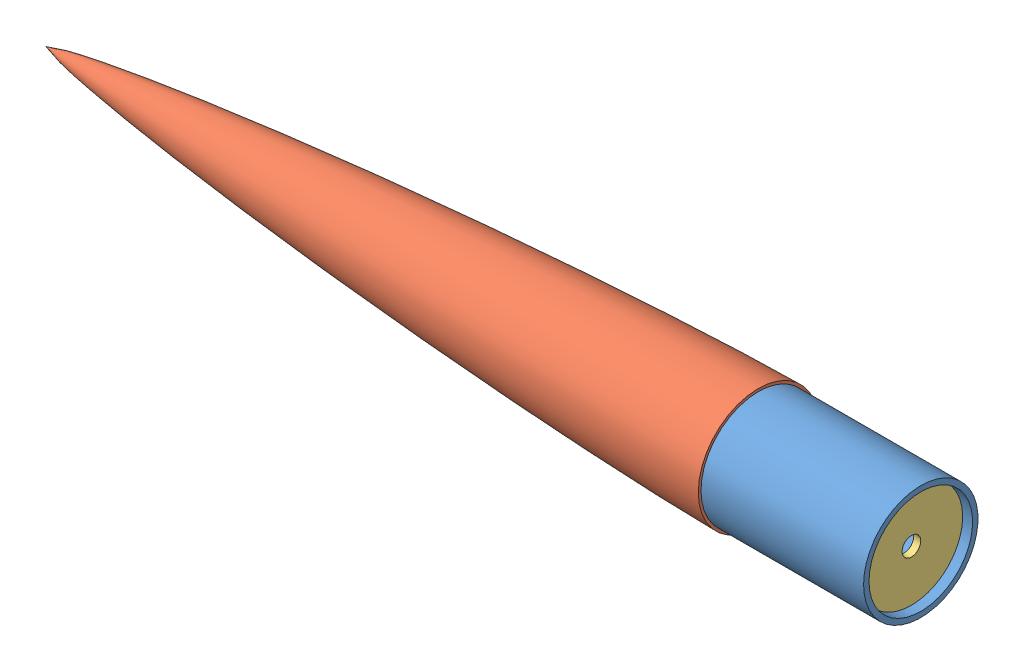
SolidWorks assembly Assem3, configuration Default. Lengths in mm.
Overall size (296.37 40.64 40.64).
3 component instances, 3 part files, 4 mates.
Components (placement in the parent):
- 3inFiberglassCoupler-1: 3inFiberglassCoupler [Default] at (-12.4673 3.7311 -16.4496) size (77.67 38.76 38.76)
- VonKarmanNoseCone-1: VonKarmanNoseCone [Default] at (-231.1613 3.7311 -16.4496) size (241.3 40.64 40.64)
- NoseConeBulkhead-1: NoseConeBulkhead [Default] at (59.6179 3.7311 -16.4496) size (2.41 34.67 34.67)
Mates (geometry in assembly coordinates):
- Concentric1: concentric aligned: cylinder of 3inFiberglassCoupler-1 through (65.2059 3.7311 -16.4496) axis (-1 0 0) radius 17.5514; circle of VonKarmanNoseCone-1
- Distance2: distance = 55.0672 mm aligned: plane of VonKarmanNoseCone-1 through (10.1387 3.7311 -16.4496) normal (1 0 0); plane of 3inFiberglassCoupler-1 through (65.2059 3.7311 -16.4496) normal (1 0 0)
- Concentric2: concentric aligned: cylinder of 3inFiberglassCoupler-1 through (65.2059 3.7311 -16.4496) axis (-1 0 0) radius 17.5514; cylinder of NoseConeBulkhead-1 through (62.0309 3.7311 -16.4496) axis (-1 0 0) radius 17.3355
- Distance3: distance = 3.175 mm aligned: plane of 3inFiberglassCoupler-1 through (65.2059 3.7311 -16.4496) normal (1 0 0); plane of NoseConeBulkhead-1 through (62.0309 3.7311 -16.4496) normal (1 0 0)
